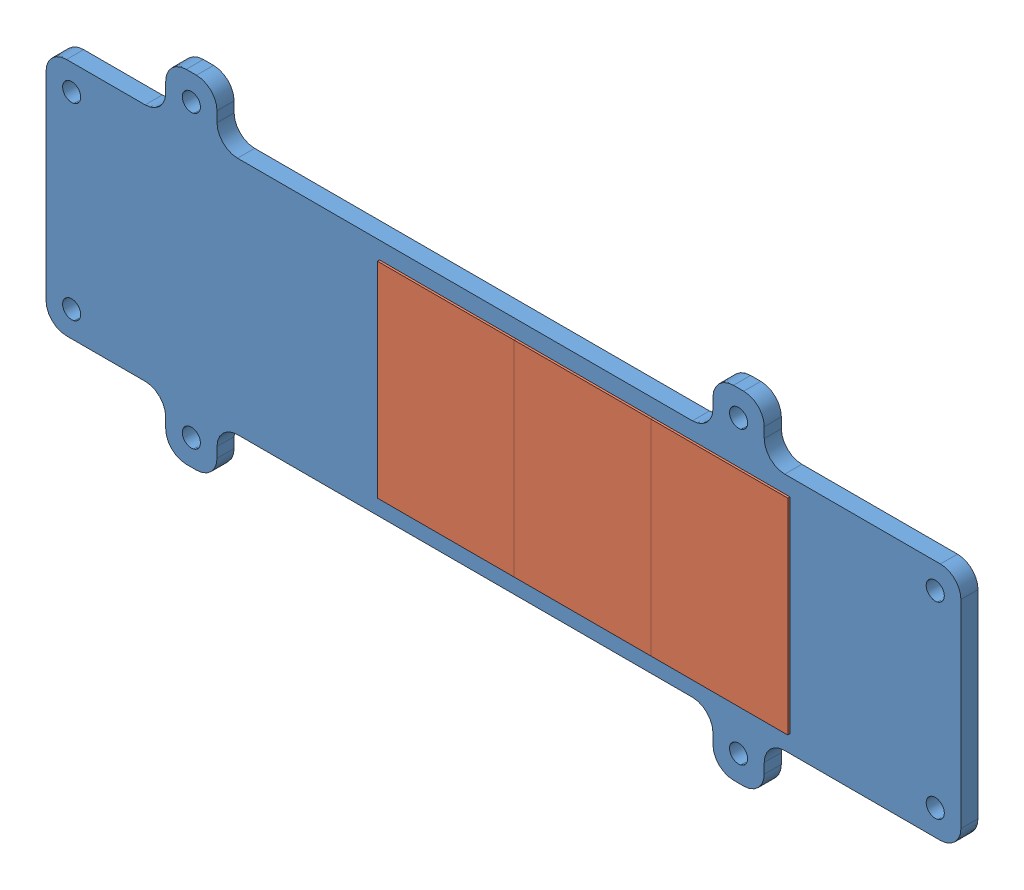
SolidWorks assembly GE-22466, configuration Default. Lengths in mm.
Overall size (339.73 127 7.14).
4 component instances, 2 part files, 9 mates.
Components (placement in the parent):
- GE-22462-1: GE-22462 [Default] at origin size (339.73 127 6.35)
- tape_SENSORDIFFUSER-1: tape_SENSORDIFFUSER [Default] at (63.5 38.1 7.1437) x (0 0 -1) z (0 1 0) size (0.79 50.8 76.2)
- tape_SENSORDIFFUSER-2: tape_SENSORDIFFUSER [Default] at (63.5 -38.1 7.1437) x (0 0 -1) z (0 -1 0) size (0.79 50.8 76.2)
- tape_SENSORDIFFUSER-3: tape_SENSORDIFFUSER [Default] at (12.7 38.1 7.1437) x (0 0 -1) z (0 1 0) size (0.79 50.8 76.2)
Mates (geometry in assembly coordinates):
- Coincident10: coincident anti-aligned: plane of lowSensorPlateAlt_mockV2-1 through (0 0 6.35) normal (0 0 1); plane of blockerTapeStrip_mockV2-1 through (63.5 38.1 6.35) normal (0 0 -1)
- Width2: width aligned: plane of lowSensorPlateAlt_mockV2-1 through (127 -44.45 6.35) normal (0 -1 0); plane of lowSensorPlateAlt_mockV2-1 through (-127 44.45 6.35) normal (0 1 0); plane of blockerTapeStrip_mockV2-1 through (63.5 -38.1 6.35) normal (0 -1 0); plane of blockerTapeStrip_mockV2-1 through (63.5 38.1 6.35) normal (0 1 0)
- Coincident9: coincident anti-aligned: plane of lowSensorPlateAlt_mockV2-1 through (0 0 6.35) normal (0 0 1); plane of blockerTapeStrip_mockV2-2 through (63.5 -38.1 6.35) normal (0 0 -1)
- Coincident3: coincident aligned: plane of blockerTapeStrip_mockV2-1 through (63.5 38.1 6.35) normal (0 1 0); plane of blockerTapeStrip_mockV2-2 through (63.5 38.1 6.35) normal (0 1 0)
- Distance3: distance = 25.4 mm: plane of blockerTapeStrip_mockV2-2 through (63.5 -38.1 7.1437) normal (1 0 0); line of lowSensorPlateAlt_mockV2-1 through (28 88.9 -14) axis (0 0 1)
- Coincident5: coincident anti-aligned: plane of blockerTapeStrip_mockV2-1 through (63.5 38.1 6.35) normal (1 0 0); plane of blockerTapeStrip_mockV2-2 through (63.5 -38.1 6.35) normal (-1 0 0)
- Coincident6: coincident anti-aligned: plane of lowSensorPlateAlt_mockV2-1 through (0 0 6.35) normal (0 0 1); plane of blockerTapeStrip_mockV2-3 through (12.7 38.1 6.35) normal (0 0 -1)
- Coincident7: coincident anti-aligned: plane of blockerTapeStrip_mockV2-1 through (12.7 38.1 6.35) normal (-1 0 0); plane of blockerTapeStrip_mockV2-3 through (12.7 38.1 6.35) normal (1 0 0)
- Coincident8: coincident aligned: plane of blockerTapeStrip_mockV2-1 through (63.5 38.1 6.35) normal (0 1 0); plane of blockerTapeStrip_mockV2-3 through (12.7 38.1 6.35) normal (0 1 0)
